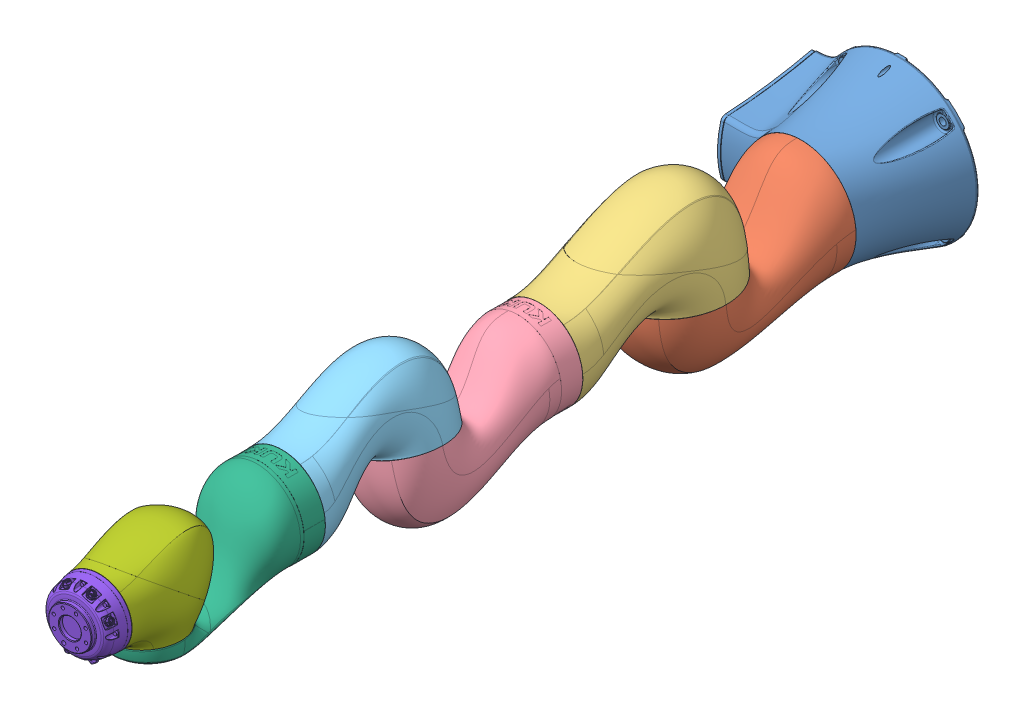
SolidWorks assembly cobot_kuka_urdf, configuration Default. Lengths in mm.
Overall size (257.48 268.8 1311.67).
8 component instances, 8 part files, 14 mates.
Components (placement in the parent):
- Copy of base^cobot_kuka_urdf-1: Copy of base^cobot_kuka_urdf [Default] at origin size (257.48 242.95 157.92) (virtual)
- Copy of link1^cobot_kuka_urdf-1: Copy of link1^cobot_kuka_urdf [Default] x (0.996886 0.078862 0) z (0 0 1) size (171.08 202.96 299.34) (virtual)
- Copy of link2^cobot_kuka_urdf-2: Copy of link2^cobot_kuka_urdf [Default] at (3.5829 0.2834 0.0177) x (0.996847 0.078859 0.008772) z (-0.008744 -0.000692 0.999962) size (171.09 201.65 291.64) (virtual)
- Copy of link3^cobot_kuka_urdf-2: Copy of link3^cobot_kuka_urdf [Default] at (3.148 0.249 0.0139) x (-0.973209 -0.22976 -0.008669) z (-0.008744 -0.000692 0.999962) size (136.09 183.99 294.72) (virtual)
- Copy of link4^cobot_kuka_urdf-2: Copy of link4^cobot_kuka_urdf [Default] at (-0.6615 -0.6503 -0.0103) x (-0.97324 -0.229761 -0.003651) z (-0.003861 0.000461 0.999992) size (136.12 183.96 254.23) (virtual)
- Copy of link5^cobot_kuka_urdf-1: Copy of link5^cobot_kuka_urdf [Default] at (-0.6615 -0.6503 -0.0103) x (0.992742 0.120206 0.003777) z (-0.003861 0.000461 0.999992) size (137.43 170.81 294.49) (virtual)
- Copy of link6^cobot_kuka_urdf-1: Copy of link6^cobot_kuka_urdf [Default] at (-102.0937 -12.9281 4.0342) x (0.989349 0.119715 -0.08281) z (0.082099 0.010866 0.996565) size (136.24 137.98 168.88) (virtual)
- Copy of fixture^cobot_kuka_urdf-1: Copy of fixture^cobot_kuka_urdf [Default] at (-102.1019 -12.9292 3.9345) x (0.343055 0.938526 -0.038495) z (0.082099 0.010866 0.996565) size (103.89 103.89 54.9) (virtual)
Mates (geometry in assembly coordinates):
- Coincident1: coincident anti-aligned: plane of base-1 through (-90 0 157.5) normal (0 0 1); plane of link1-1 through (-6.5061 82.2431 157.5) normal (0 0 -1)
- Concentric1: concentric anti-aligned: cylinder of base-1 through (0 0 0) axis (0 0 1) radius 25; cylinder of link1-1 through (0 0 157.5) axis (0 0 -1) radius 25
- Coincident3: coincident anti-aligned: plane of Copy of link1^cobot_kuka_r1-1 through (0 0 335) normal (-0.078862 0.996886 0); plane of link2-2 through (0.7214 0.0571 277.5032) normal (0.078862 -0.996886 0)
- Concentric2: concentric anti-aligned: cylinder of Copy of link1^cobot_kuka_r1-1 through (11.8007 -149.1715 360) axis (-0.078862 0.996886 0) radius 25; cylinder of link2-2 through (0 0 360) axis (0.078862 -0.996886 0) radius 25
- Coincident11: coincident anti-aligned: plane of Copy of link2^cobot_kuka_r1-2 through (-6.8354 63.6592 564.4921) normal (-0.008744 -0.000692 0.999962); plane of Copy of link3^cobot_kuka_urdf-2 through (-1.7882 -0.1415 564.4921) normal (0.008744 0.000692 -0.999962)
- Concentric6: concentric aligned: cylinder of Copy of link2^cobot_kuka_r1-2 through (-1.7839 -0.1411 563.9922) axis (0.008744 0.000692 -0.999962) radius 25; cylinder of Copy of link3^cobot_kuka_urdf-2 through (-1.7882 -0.1415 564.4921) axis (0.008744 0.000692 -0.999962) radius 25
- Coincident13: coincident anti-aligned: plane of Copy of link3^cobot_kuka_urdf-2 through (-2.9828 -0.7317 714.237) normal (-0.229757 0.973247 -0.001336); plane of Copy of link4^cobot_kuka_urdf-2 through (-3.3059 -0.8073 714.735) normal (0.229757 -0.973247 0.001336)
- Concentric7: concentric aligned: cylinder of Copy of link3^cobot_kuka_urdf-2 through (-3.5578 -0.7772 779.9845) axis (0.229757 -0.973247 0.001336) radius 25; cylinder of Copy of link4^cobot_kuka_urdf-2 through (-3.5578 -0.7772 779.9845) axis (0.229757 -0.973247 0.001336) radius 25
- Coincident14: coincident anti-aligned: plane of Copy of link4^cobot_kuka_urdf-2 through (-19.0894 62.0824 964.3969) normal (-0.003861 0.000461 0.999992); plane of Copy of link5^cobot_kuka_urdf-1 through (-4.3849 -0.2054 964.4824) normal (0.003861 -0.000461 -0.999992)
- Concentric8: concentric aligned: cylinder of Copy of link4^cobot_kuka_urdf-2 through (-4.383 -0.2057 963.9825) axis (0.003861 -0.000461 -0.999992) radius 25; cylinder of Copy of link5^cobot_kuka_urdf-1 through (-4.3849 -0.2054 964.4824) axis (0.003861 -0.000461 -0.999992) radius 25
- Coincident15: coincident anti-aligned: plane of Copy of link5^cobot_kuka_urdf-1 through (1.9594 -60.3354 1228.5366) normal (-0.120204 0.992749 -0.000922); plane of Copy of link6^cobot_kuka_urdf-1 through (6.5129 -59.7791 1233.8513) normal (0.120204 -0.992749 0.000922)
- Concentric9: concentric aligned: cylinder of Copy of link5^cobot_kuka_urdf-1 through (2.0795 -60.3659 1180.0368) axis (0.120204 -0.992749 0.000922) radius 25; cylinder of Copy of link6^cobot_kuka_urdf-1 through (1.9954 -59.671 1180.0361) axis (0.120204 -0.992749 0.000922) radius 25
- Coincident16: coincident anti-aligned: plane of Copy of link6^cobot_kuka_urdf-1 through (-4.465 49.4177 1260.5577) normal (0.082099 0.010866 0.996565); plane of Copy of fixture^cobot_kuka_urdf-1 through (39.1448 -34.1029 1257.8758) normal (-0.082099 -0.010866 -0.996565)
- Concentric10: concentric anti-aligned: cylinder of Copy of link6^cobot_kuka_urdf-1 through (1.3839 0.7676 1260.1046) axis (-0.082099 -0.010866 -0.996565) radius 25; cylinder of Copy of fixture^cobot_kuka_urdf-1 through (0.6122 0.6655 1250.7369) axis (0.082099 0.010866 0.996565) radius 25
